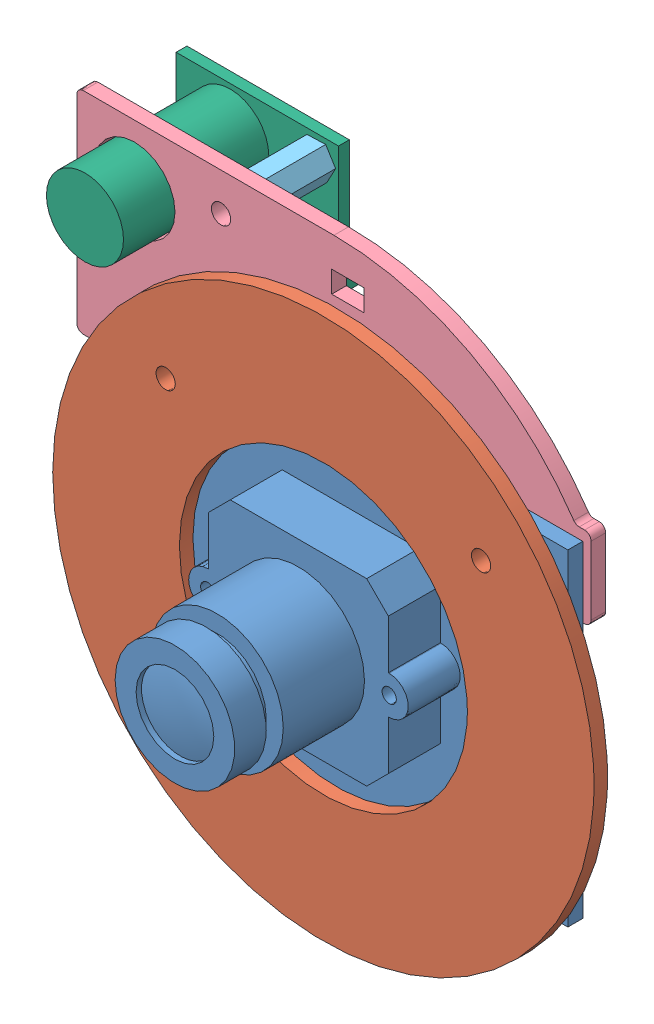
SolidWorks assembly cam w_lightring-thermal, configuration Default. Lengths in mm.
Overall size (65.6 67.4 37.26).
8 component instances, 6 part files, 28 mates.
Components (placement in the parent):
- RCM-Cam-1: RCM-Cam [Default] at origin size (51 38.31 29.45)
- light-ring-1: light-ring [Default] at (0 0 3.3401) size (63.5 63.5 1.59)
- Standoff-spacer-1: Standoff-spacer [Default] at (44 35.31 3.3401) x (0.99572 -0.092426 0) z (0.092426 0.99572 0) size (6.35 1.59 6.35)
- Standoff-spacer-2: Standoff-spacer [Default] at (7 35.31 3.3401) x (0.918204 -0.396107 0) z (0.396107 0.918204 0) size (6.35 1.59 6.35)
- thermalsensor_mount2-1: thermalsensor_mount2 [Default] at (21.8131 20.7945 0) x (-1 0 0) z (0 0 -1) size (60.32 24.77 1.71)
- 375 standoff-1: 375 standoff [Default] at (8.571 50.3595 -1.7145) x (0.469157 0.883115 0) z (-0.883115 0.469157 0) size (4.4 9.53 3.81)
- 375 standoff-2: 375 standoff [Default] at (-5.399 41.4695 -1.7145) x (0.469157 0.883115 0) z (-0.883115 0.469157 0) size (4.4 9.53 3.81)
- Thermal-1: Thermal [Default] at (-7.939 52.8995 -12.5095) x (0 -1 0) z (0 0 1) size (21.34 19.05 20.73)
Mates (geometry in assembly coordinates):
- Concentric1: concentric: cylinder of RCM-Cam-1 through (44 35.31 -4.4901) axis (0 0 1) radius 1.5875; cylinder of light-ring-1 through (44 35.31 8.1246) axis (0 0 -1) radius 1.1303
- Concentric2: concentric: cylinder of RCM-Cam-1 through (7 35.31 -4.4901) axis (0 0 1) radius 1.5875; cylinder of light-ring-1 through (7 35.31 8.1246) axis (0 0 -1) radius 1.1303
- Concentric3: concentric: cylinder of RCM-Cam-1 through (25.5 19.155 17.3736) axis (0 0 -1) radius 7.747; cylinder of light-ring-1 through (25.5 19.155 4.9276) axis (0 0 -1) radius 16.891
- Concentric5: concentric: cylinder of RCM-Cam-1 through (44 35.31 -4.4901) axis (0 0 1) radius 1.5875; cylinder of ? through (44 35.31 -16.0274) axis (0 0 1) radius 1.5875
- Concentric6: concentric: cylinder of RCM-Cam-1 through (7 35.31 -4.4901) axis (0 0 1) radius 1.5875; cylinder of ? through (7 35.31 6.8326) axis (0 0 -1) radius 1.5875
- Concentric8: concentric: cylinder of ? through (27.4253 17.4411 -7.7016) axis (1 0 0) radius 4.064; cylinder of ? through (75.1291 17.4411 -7.7016) axis (-1 0 0) radius 2.5019
- Concentric15: concentric: cylinder of ? through (48.953 8.8686 -7.7016) axis (1 0 0) radius 1.7272; cylinder of ? through (55.5464 8.8686 -7.7016) axis (1 0 0) radius 2.159
- Concentric16: concentric: cylinder of ? through (48.953 26.0136 -7.7016) axis (1 0 0) radius 1.7272; cylinder of ? through (55.5464 26.0136 -7.7016) axis (1 0 0) radius 2.159
- Concentric17: concentric: cylinder of ? through (4.587 8.8686 -7.7016) axis (-1 0 0) radius 1.7272; cylinder of ? through (-4.8618 8.8686 -7.7016) axis (-1 0 0) radius 2.159
- Concentric18: concentric: cylinder of ? through (4.587 26.0136 -7.7016) axis (-1 0 0) radius 1.7272; cylinder of ? through (-4.8618 26.0136 -7.7016) axis (-1 0 0) radius 2.159
- Concentric19: concentric: cylinder of ? through (54.3886 4.6395 -6.5024) axis (0 0 -1) radius 1.7272; cylinder of ? through (54.3886 4.6395 -17.7419) axis (0 0 1) radius 2.159
- Concentric20: concentric: cylinder of ? through (-0.1374 4.6395 -6.5024) axis (0 0 -1) radius 1.7272; cylinder of ? through (-0.1374 4.6395 -17.7419) axis (0 0 1) radius 2.159
- Concentric21: concentric: cylinder of ? through (56.1626 -1.52 -21.5519) axis (0 0 -1) radius 1.5875; cylinder of ? through (56.1626 -1.52 -17.7419) axis (0 0 1) radius 1.1303
- Coincident1: coincident: plane of RCM-Cam-1 through (0 0 1.7526) normal (0 0 1); plane of Standoff-spacer-1 through (44 35.31 1.7526) normal (0 0 -1)
- Concentric22: concentric: cylinder of RCM-Cam-1 through (44 35.31 -4.4901) axis (0 0 1) radius 1.5875; cylinder of Standoff-spacer-1 through (44 35.31 1.7526) axis (0 0 1) radius 1.4605
- Coincident2: coincident: plane of RCM-Cam-1 through (0 0 1.7526) normal (0 0 1); plane of Standoff-spacer-2 through (7 35.31 1.7526) normal (0 0 -1)
- Concentric23: concentric: cylinder of RCM-Cam-1 through (7 35.31 -4.4901) axis (0 0 1) radius 1.5875; cylinder of Standoff-spacer-2 through (7 35.31 1.7526) axis (0 0 1) radius 1.4605
- Coincident3: coincident: plane of light-ring-1 through (25.5 19.155 3.3401) normal (0 0 -1); plane of Standoff-spacer-1 through (44 35.31 3.3401) normal (0 0 1)
- Coincident4: coincident: plane of RCM-Cam-1 through (0 0 0) normal (0 0 -1); plane of thermalsensor_mount2-1 through (21.8131 20.7945 0) normal (0 0 1)
- Concentric24: concentric: cylinder of RCM-Cam-1 through (44 35.31 -4.4901) axis (0 0 1) radius 1.5875; cylinder of thermalsensor_mount2-1 through (44 35.31 -1.7145) axis (0 0 1) radius 1.1303
- Concentric25: concentric: cylinder of RCM-Cam-1 through (7 35.31 -4.4901) axis (0 0 1) radius 1.5875; cylinder of thermalsensor_mount2-1 through (7 35.31 -1.7145) axis (0 0 1) radius 1.1303
- Concentric26: concentric: cylinder of thermalsensor_mount2-1 through (8.571 50.3595 -1.7145) axis (0 0 1) radius 1.1303; cylinder of 375 standoff-1 through (8.571 50.3595 -11.2395) axis (0 0 1) radius 1.1303
- Coincident5: coincident: plane of thermalsensor_mount2-1 through (21.8131 20.7945 -1.7145) normal (0 0 -1); plane of 375 standoff-1 through (8.571 50.3595 -1.7145) normal (0 0 1)
- Concentric27: concentric: cylinder of thermalsensor_mount2-1 through (-5.399 41.4695 -1.7145) axis (0 0 1) radius 1.1303; cylinder of 375 standoff-2 through (-5.399 41.4695 -11.2395) axis (0 0 1) radius 1.1303
- Coincident6: coincident: plane of thermalsensor_mount2-1 through (21.8131 20.7945 -1.7145) normal (0 0 -1); plane of 375 standoff-2 through (-5.399 41.4695 -1.7145) normal (0 0 1)
- Concentric28: concentric: cylinder of thermalsensor_mount2-1 through (8.571 50.3595 -1.7145) axis (0 0 1) radius 1.1303; cylinder of Thermal-1 through (8.571 50.3595 -11.2395) axis (0 0 -1) radius 1.5875
- Concentric29: concentric: cylinder of thermalsensor_mount2-1 through (-5.399 41.4695 -1.7145) axis (0 0 1) radius 1.1303; cylinder of Thermal-1 through (-5.399 41.4695 -11.2395) axis (0 0 -1) radius 1.5875
- Coincident7: coincident: plane of 375 standoff-2 through (-5.399 41.4695 -11.2395) normal (0 0 -1); plane of Thermal-1 through (-7.939 52.8995 -11.2395) normal (0 0 1)
